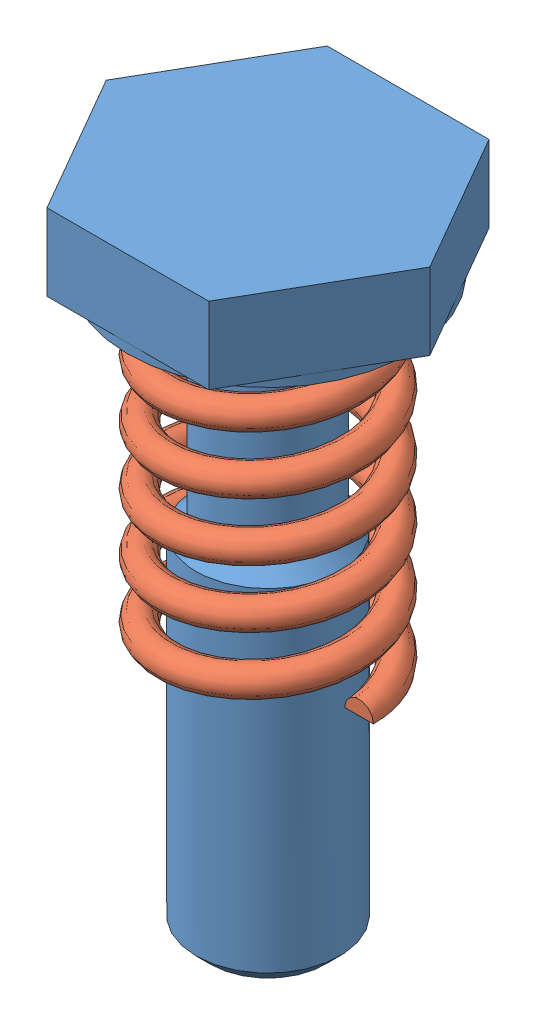
SolidWorks assembly Spring-bolt, configuration M2,5. Lengths in mm.
Overall size (6.75 13.7 5.85).
3 component instances, 3 part files, 4 mates.
Components (placement in the parent):
- Гайка PF-1: Гайка PF [M2,5] at origin (suppressed, hidden)
- Bolt-1: Bolt [M3 PF] at (0.0665 9.98 0.4927)
- Spring-1: Spring [M2,5 U] at (0.0665 2.93 0.4927) size (4.51 7.85 4.4)
Mates (geometry in assembly coordinates):
- Концентричный1: concentric anti-aligned: cylinder of Гайка PF-1 through (0 0 0) axis (0 -1 0) radius 1.5; cylinder of Винт PF-1 through (0.0665 9.98 0.4927) axis (0 1 0) radius 1.5
- Совпадение1: coincident aligned: plane of Гайка PF-1 through (0 0 0) normal (0 0 1); plane of Винт PF-1 through (0.0665 9.98 0.4927) normal (0 0 1)
- Концентричный2: concentric anti-aligned: cylinder of Винт PF-1 through (0.0665 9.98 0.4927) axis (0 1 0) radius 1.5; line of Пружина PF-1 through (0.0665 52.93 0.4927) axis (0 -1 0)
- Совпадение3: coincident anti-aligned: plane of Винт PF-1 through (0.0665 10.18 0.4927) normal (0 -1 0); plane of Пружина PF-1 through (-17.134 10.18 -1.7073) normal (0 1 0)
